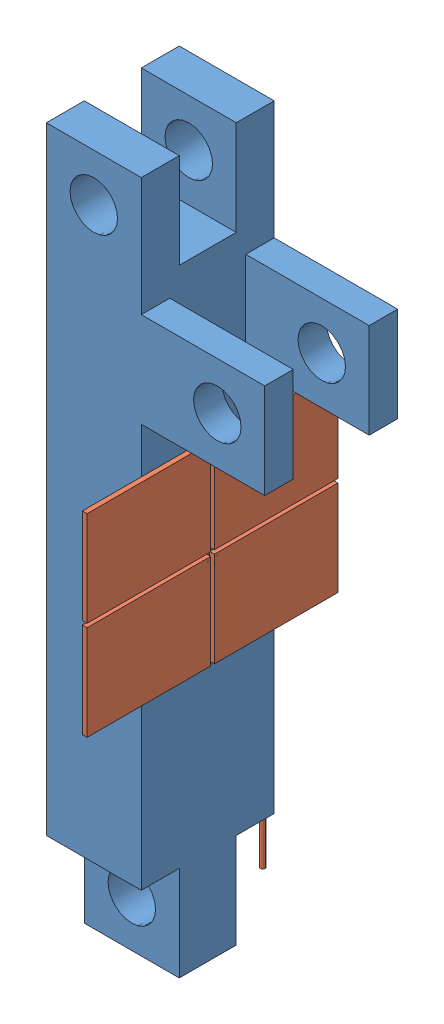
SolidWorks assembly ConnectionUnit, configuration 默认. Lengths in mm.
Overall size (23 75 26.4).
2 component instances, 2 part files, 3 mates.
Components (placement in the parent):
- ConnectionRod-IV-1: ConnectionRod-IV [默认] at (-16.742 6.238 75) size (23 75 14)
- RealSiPMArray-1: RealSiPMArray [默认] at (-11.242 1.238 75) x (-1 0 0) z (0 0 -1) size (3.97 70 26.4)
Mates (geometry in assembly coordinates):
- 重合11: coincident anti-aligned: plane of ConnectionRod-IV-1 through (-11.742 38.738 68) normal (1 0 0); plane of RealSiPMArray-1 through (-11.742 1.238 75) normal (-1 0 0)
- 重合12: coincident: point of ConnectionRod-IV-1; point of RealSiPMArray-1
- 平行2: parallel anti-aligned: line of ConnectionRod-IV-1 through (-11.742 6.238 82) axis (0 -1 0); line of RealSiPMArray-1 through (-11.242 0.738 74.5) axis (0 1 0)
